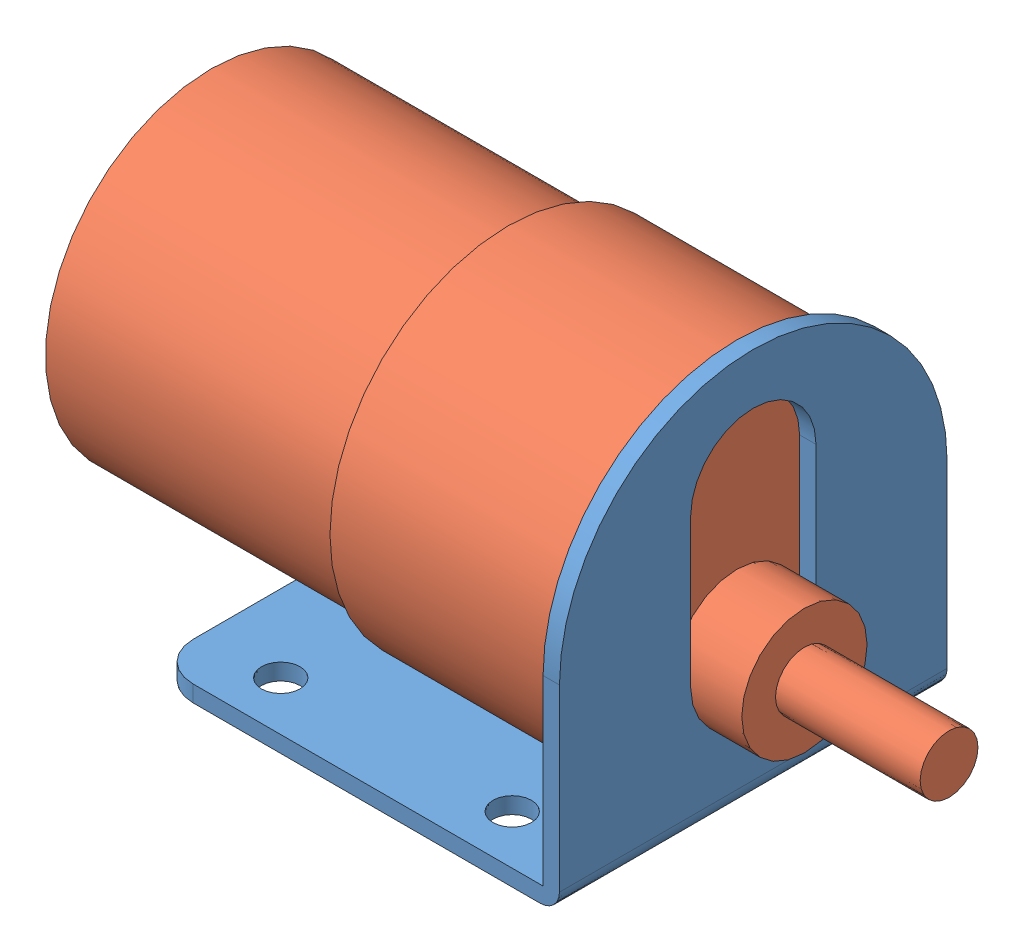
SolidWorks assembly moteur+support, configuration Default. Lengths in mm.
Overall size (79.5 40.7 40.2).
2 component instances, 2 part files, 3 mates.
Components (placement in the parent):
- supportMoteur-1: supportMoteur [Default] at (46.2429 19.2403 29.8006) size (42 40.7 40.2)
- moteurKacem-1: moteurKacem [Default] at (22.5429 38.1403 49.9006) x (-1 0 0) z (0 0 -1) size (79.5 37 37)
Mates (geometry in assembly coordinates):
- Coincident1: coincident anti-aligned: plane of supportMoteur-1 through (46.2429 19.2403 70.0006) normal (-1 0 0); plane of moteurKacem-1 through (46.2429 38.1403 49.9006) normal (1 0 0)
- Concentric2: concentric aligned: cylinder of supportMoteur-1 through (47.9429 38.1403 49.9006) axis (-1 0 0) radius 20.1; cylinder of moteurKacem-1 through (-8.2571 38.1403 49.9006) axis (-1 0 0) radius 18.5
- Width1: width: plane of supportMoteur-1 through (9.9429 31.3675 43.4006) normal (0 0 1); plane of supportMoteur-1 through (9.9429 31.3675 56.4006) normal (0 0 -1); cylinder of moteurKacem-1 through (53.2429 31.1403 49.9006) axis (-1 0 0) radius 6.5
